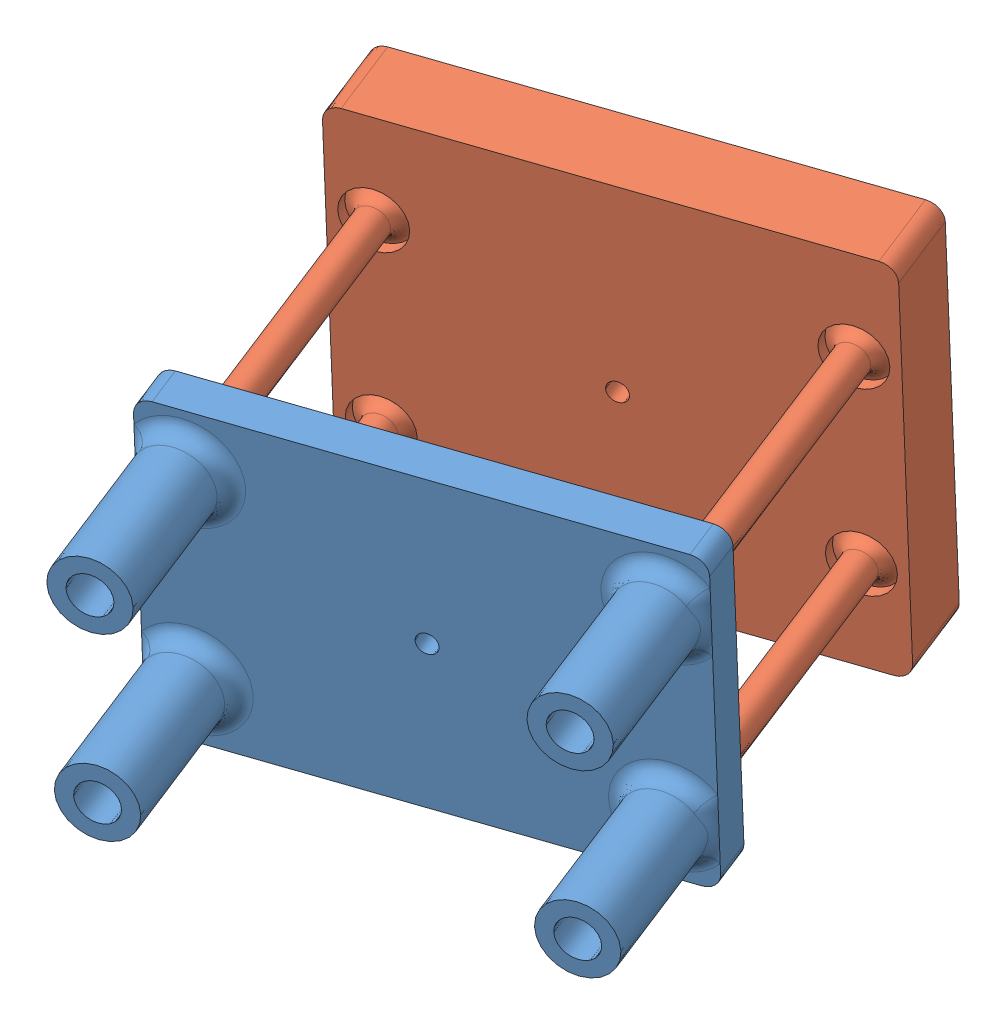
SolidWorks assembly Assemblage1, configuration Défaut. Lengths in mm.
Overall size (81 52.99 89.45).
2 component instances, 2 part files, 3 mates.
Components (placement in the parent):
- plaqueinf-1: plaqueinf [Défaut] at (25.1534 45.8667 18.5078) x (-0.945137 0.003724 0.326654) z (-0.32554 0.072539 -0.942742) size (60 40 25)
- plaquesup-1: plaquesup [Défaut] at (-46.3528 54.4046 -4.804) x (0.945137 -0.003724 -0.326654) z (0.32554 -0.072539 0.942742) size (60 50 40)
Mates (geometry in assembly coordinates):
- Coaxiale1: concentric aligned: cylinder of plaqueinf-1 through (-5.3725 26.3939 22.2468) axis (0.32554 -0.072539 0.942742) radius 1.25; cylinder of plaquesup-1 through (-20.3065 29.7216 -21.001) axis (0.32554 -0.072539 0.942742) radius 1.25
- Coaxiale2: concentric aligned: cylinder of plaqueinf-1 through (-21.2025 12.2065 53.1398) axis (-0.32554 0.072539 -0.942742) radius 2.5; cylinder of plaquesup-1 through (-31.2534 14.4461 24.0331) axis (-0.32554 0.072539 -0.942742) radius 2
- Coïncidente3: coincident anti-aligned: plane of plaqueinf-1 through (19.0262 48.0718 18.7253) normal (-0.32554 0.072539 -0.942742); plane of plaquesup-1 through (-37.546 53.2821 38.6612) normal (0.32554 -0.072539 0.942742)
